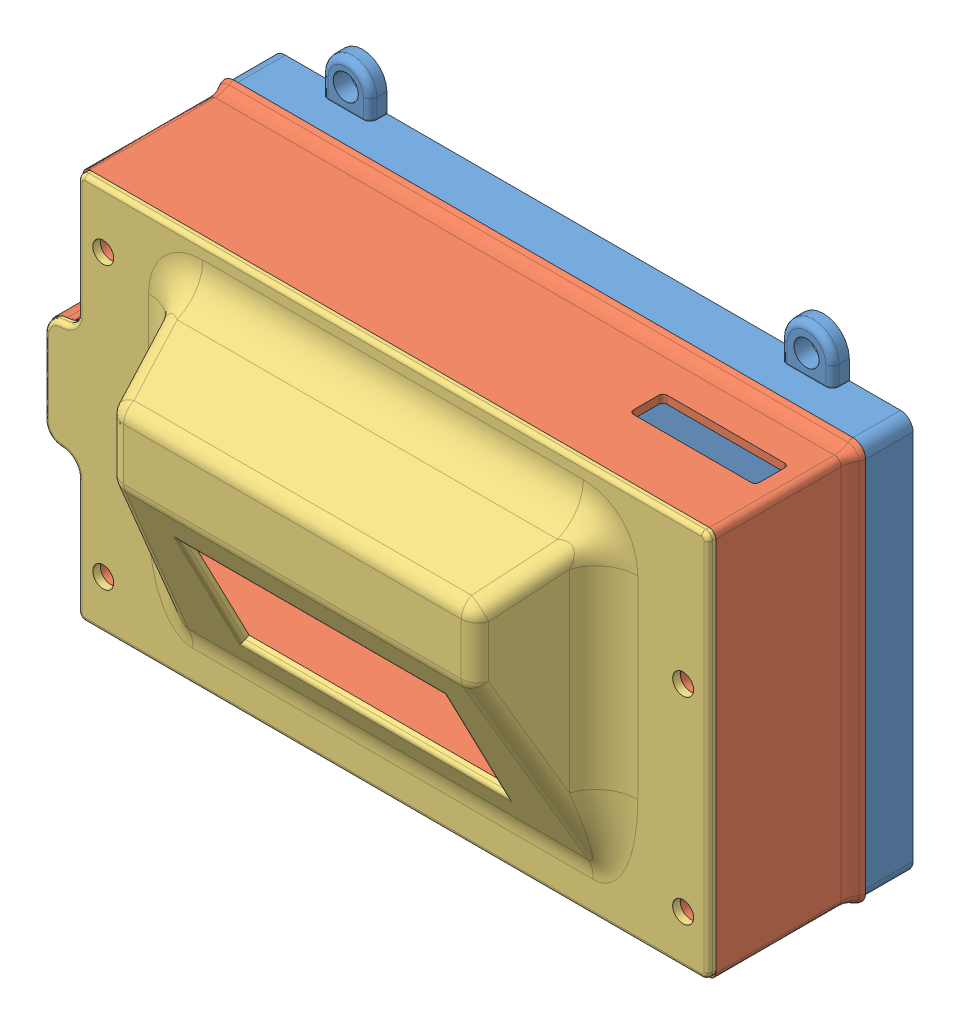
SolidWorks assembly Assem1, configuration Default. Lengths in mm.
Overall size (80.68 58.1 36.05).
3 component instances, 3 part files, 6 mates.
Components (placement in the parent):
- BoxBottomV3-1: BoxBottomV3 [Défaut] at (-12.1013 10.2583 -0.5837) size (76.3 58.1 6)
- BoxMiddleV3-1: BoxMiddleV3 [Défaut] at (-12.0013 10.3583 -0.5837) size (79.83 47.8 19.15)
- BoxTopV2-1: BoxTopV2 [Défaut] at (-11.8513 10.5083 -3.5837) size (79.98 46.1 13.38)
Mates (geometry in assembly coordinates):
- Coincident1: coincident: plane of BoxBottomV3-1 through (-41.0513 39.3083 3.4163) normal (0 0 1); plane of BoxMiddleV3-1 through (-41.2013 39.7083 3.4163) normal (0 0 -1)
- Coincident2: coincident: plane of BoxBottomV3-1 through (-40.2513 33.2083 -0.5837) normal (0 -1 0); plane of BoxMiddleV3-1 through (31.8102 33.2083 5.4163) normal (0 1 0)
- Coincident3: coincident anti-aligned: plane of BoxBottomV3-1 through (33.8487 32.4083 -0.5837) normal (-1 0 0); plane of BoxMiddleV3-1 through (33.8487 -11.0917 5.4163) normal (1 0 0)
- Coincident4: coincident: plane of BoxMiddleV3-1 through (-12.0013 10.3583 22.5663) normal (0 0 1); plane of BoxTopV2-1 through (-11.8513 10.5083 22.5663) normal (0 0 -1)
- Coincident5: coincident: line of BoxMiddleV3-1 through (34.1987 -12.0417 22.5663) axis (0 1 0); line of BoxTopV2-1 through (34.1987 -11.7417 22.5663) axis (0 1 0)
- Coincident6: coincident aligned: line of BoxMiddleV3-1 through (33.3987 33.5583 22.5663) axis (-1 0 0); line of BoxTopV2-1 through (33.3987 33.5583 22.5663) axis (-1 0 0)
